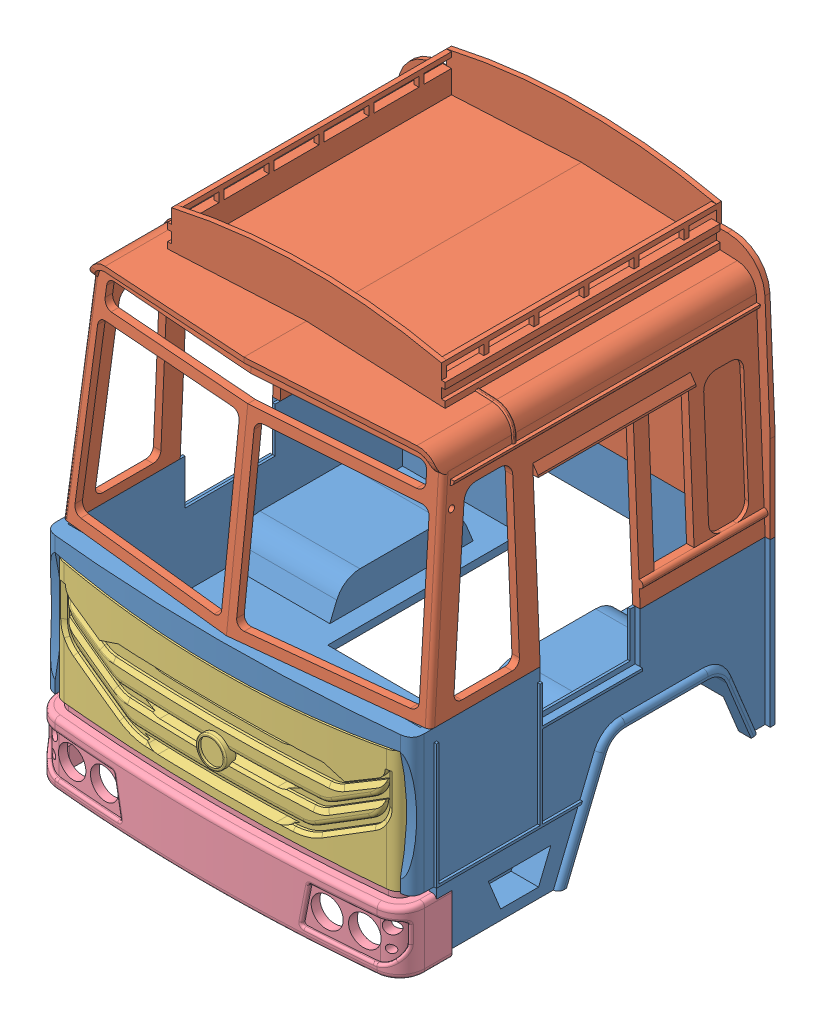
SolidWorks assembly avtrassembly, configuration Default. Lengths in mm.
Overall size (152.54 194.82 159.83).
4 component instances, 4 part files, 3 mates.
Components (placement in the parent):
- 1_14 ashok leyland AVTR2-1: 1_14 ashok leyland AVTR2 [Default] at (66.8096 45.7214 191.0876) size (152.54 95.14 159.83)
- cabin top-1: cabin top [Default] at (70.2962 100.7214 120.9728) x (0 0 -1) z (1 0 0) size (144 111.39 151)
- 1_14 ashok leyland AVTR_small_cowl-1: 1_14 ashok leyland AVTR_small_cowl [Default] at (66.4998 45.1803 191.2565) size (138.07 66.99 28.32)
- 1_14 ashok leyland AVTR_lower_bumber-1: 1_14 ashok leyland AVTR_lower_bumber [Default] at (66.8672 17.3026 188.372) size (147.02 30.02 24.02)
Mates (geometry in assembly coordinates):
- Coincident12: coincident aligned: plane of 1_14 ashok leyland AVTR2-1 through (142.3096 45.7214 191.0876) normal (1 0 0); plane of cabin top-1 through (142.3096 193.7214 51.0876) normal (1 0 0)
- Coincident13: coincident aligned: plane of 1_14 ashok leyland AVTR2-1 through (-9.4613 100.7214 103.0876) normal (0 0 1); plane of cabin top-1 through (-8.6904 165.7214 103.0876) normal (0 0 1)
- Coincident14: coincident anti-aligned: plane of 1_14 ashok leyland AVTR2-1 through (66.8096 100.7214 -479.1936) normal (0 1 0); plane of cabin top-1 through (70.2962 100.7214 120.9728) normal (0 -1 0)
